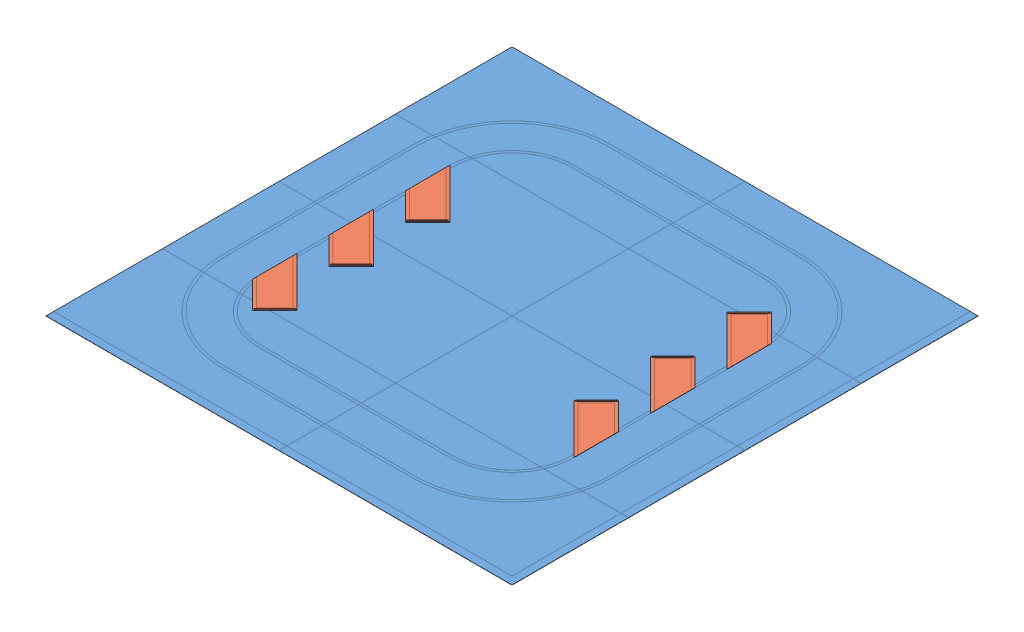
SolidWorks assembly AV_Comp_Mech_1_4_1_Environment, configuration Default. Lengths in mm.
Overall size (4880 14 4880).
8 component instances, 3 part files, 13 mates.
Components (placement in the parent):
- AV_Comp_Mech_1_4_2_Corflute_Sheet-1: AV_Comp_Mech_1_4_2_Corflute_Sheet [1] at (2440 0 2440) size (4880 2 4880)
- AV_Comp_Mech_1_4_3_Environment_Sketch-1: AV_Comp_Mech_1_4_3_Environment_Sketch [Default] at (2400 0 2400) size (4800 0 4800) (hidden)
- Parking_lot-7: Parking_lot [Default] at (1266.188 2 1916.188) x (0 0 1) z (-1 0 0) size (749.53 12 516.19)
- Parking_lot-10: Parking_lot [Default] at (1266.188 2 2716.188) x (0 0 1) z (-1 0 0) size (749.53 12 516.19)
- Parking_lot-11: Parking_lot [Default] at (1266.188 2 3516.188) x (0 0 1) z (-1 0 0) size (749.53 12 516.19)
- Parking_lot-12: Parking_lot [Default] at (3533.812 2 2883.812) x (0 0 -1) z (1 0 0) size (749.53 12 516.19)
- Parking_lot-13: Parking_lot [Default] at (3533.812 2 2083.812) x (0 0 -1) z (1 0 0) size (749.53 12 516.19)
- Parking_lot-14: Parking_lot [Default] at (3533.812 2 1283.812) x (0 0 -1) z (1 0 0) size (749.53 12 516.19)
Mates (geometry in assembly coordinates):
- Coincident1: coincident: point of AV_Comp_Mech_1_4_3_Environment_Sketch-1; point of assembly
- Coincident3: coincident: unknown of AV_Comp_Mech_1_4_2_Cortflute_Sheet-1
- Coincident4: coincident: line of AV_Comp_Mech_1_4_1_Environment-1 through (0 4800 0) axis (0 0 1)
- Coincident5: coincident anti-aligned: line of AV_Comp_Mech_1_4_2_Cortflute_Sheet-1 through (0 2440 4880) axis (0 0 -1); line of AV_Comp_Mech_1_4_1_Environment-1 through (0 4800 0) axis (0 0 1)
- Coincident6: coincident anti-aligned: line of AV_Comp_Mech_1_4_2_Cortflute_Sheet-1 through (0 0 0) axis (0 0 1); line of AV_Comp_Mech_1_4_1_Environment-1 through (0 0 4800) axis (0 0 -1)
- Coincident7: coincident: line of AV_Comp_Mech_1_4_1_Environment-1 through (0 0 4800) axis (0 0 -1)
- Coincident8: coincident: line of AV_Comp_Mech_1_4_1_Environment-1 through (0 0 4800) axis (1 0 0)
- Coincident42: coincident anti-aligned: plane of AV_Comp_Mech_1_4_2_Corflute_Sheet-1 through (2440 2 2440) normal (0 1 0); plane of Parking_lot-7 through (1266.188 2 1916.188) normal (0 -1 0)
- Coincident65: coincident aligned: line of AV_Comp_Mech_1_4_2_Corflute_Sheet-1 through (750 2 1400) axis (0 0 1); line of Parking_lot-7 through (750 2 1400) axis (0 0 1)
- Coincident66: coincident: point of AV_Comp_Mech_1_4_2_Corflute_Sheet-1; point of Parking_lot-7
- Coincident67: coincident aligned: line of AV_Comp_Mech_1_4_2_Corflute_Sheet-1 through (4050 2 3400) axis (0 0 -1); line of Parking_lot-12 through (4050 2 3400) axis (0 0 -1)
- Coincident68: coincident anti-aligned: plane of AV_Comp_Mech_1_4_2_Corflute_Sheet-1 through (2440 2 2440) normal (0 1 0); plane of Parking_lot-12 through (3533.812 2 2883.812) normal (0 -1 0)
- Coincident69: coincident: point of AV_Comp_Mech_1_4_2_Corflute_Sheet-1; point of Parking_lot-12
